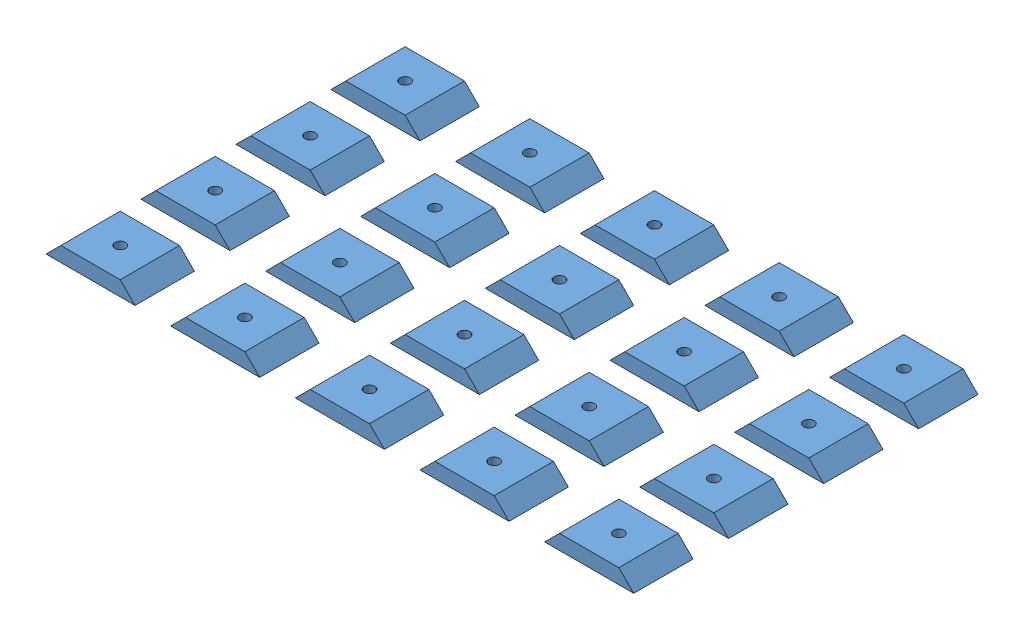
SolidWorks assembly Pressure_Port_Nut_WAterjet_Layout, configuration Default. Lengths in mm.
Overall size (125.73 3.17 73.66).
32 component instances, 2 part files, 3 mates.
Components (placement in the parent):
- Pressure_Port_Cover_Nut-1: Pressure_Port_Cover_Nut [Default] at (-34.8139 9.8282 11.9389) size (19.05 3.17 12.7)
- Pressure_Port_Cover_Nut-3: Pressure_Port_Cover_Nut [Default] at (-8.1439 9.8282 11.9389) size (19.05 3.17 12.7)
- Pressure_Port_Cover_Nut-4: Pressure_Port_Cover_Nut [Default] at (-34.8139 9.8282 32.2589) size (19.05 3.17 12.7)
- Pressure_Port_Cover_Nut-5: Pressure_Port_Cover_Nut [Default] at (-34.8139 9.8282 52.5789) size (19.05 3.17 12.7)
- Pressure_Port_Cover_Nut-6: Pressure_Port_Cover_Nut [Default] at (-34.8139 9.8282 72.8989) size (19.05 3.17 12.7)
- Pressure_Port_Cover_Nut-7: Pressure_Port_Cover_Nut [Default] at (-8.1439 9.8282 32.2589) size (19.05 3.17 12.7)
- Pressure_Port_Cover_Nut-8: Pressure_Port_Cover_Nut [Default] at (-8.1439 9.8282 52.5789) size (19.05 3.17 12.7)
- Pressure_Port_Cover_Nut-9: Pressure_Port_Cover_Nut [Default] at (-8.1439 9.8282 72.8989) size (19.05 3.17 12.7)
- Pressure_Port_Cover_Nut-10: Pressure_Port_Cover_Nut [Default] at (18.5261 9.8282 11.9389) size (19.05 3.17 12.7)
- Pressure_Port_Cover_Nut-11: Pressure_Port_Cover_Nut [Default] at (18.5261 9.8282 32.2589) size (19.05 3.17 12.7)
- Pressure_Port_Cover_Nut-12: Pressure_Port_Cover_Nut [Default] at (18.5261 9.8282 52.5789) size (19.05 3.17 12.7)
- Pressure_Port_Cover_Nut-13: Pressure_Port_Cover_Nut [Default] at (18.5261 9.8282 72.8989) size (19.05 3.17 12.7)
- Pressure_Port_Cover_Nut-14: Pressure_Port_Cover_Nut [Default] at (45.1961 9.8282 11.9389) size (19.05 3.17 12.7)
- Pressure_Port_Cover_Nut-15: Pressure_Port_Cover_Nut [Default] at (45.1961 9.8282 32.2589) size (19.05 3.17 12.7)
- Pressure_Port_Cover_Nut-16: Pressure_Port_Cover_Nut [Default] at (45.1961 9.8282 52.5789) size (19.05 3.17 12.7)
- Pressure_Port_Cover_Nut-17: Pressure_Port_Cover_Nut [Default] at (45.1961 9.8282 72.8989) size (19.05 3.17 12.7)
- Pressure_Port_Cover_Nut-18: Pressure_Port_Cover_Nut [Default] at (71.8661 9.8282 11.9389) size (19.05 3.17 12.7)
- Pressure_Port_Cover_Nut-19: Pressure_Port_Cover_Nut [Default] at (71.8661 9.8282 32.2589) size (19.05 3.17 12.7)
- Pressure_Port_Cover_Nut-20: Pressure_Port_Cover_Nut [Default] at (71.8661 9.8282 52.5789) size (19.05 3.17 12.7)
- Pressure_Port_Cover_Nut-21: Pressure_Port_Cover_Nut [Default] at (71.8661 9.8282 72.8989) size (19.05 3.17 12.7)
- Pressure_Port_Nut_Waterjet_Tabs-1: Pressure_Port_Nut_Waterjet_Tabs [Default] at (-19.5739 12.3682 23.3689) (suppressed, hidden)
- Pressure_Port_Nut_Waterjet_Tabs-2: Pressure_Port_Nut_Waterjet_Tabs [Default] at (-19.5739 12.3682 43.6889) (suppressed, hidden)
- Pressure_Port_Nut_Waterjet_Tabs-3: Pressure_Port_Nut_Waterjet_Tabs [Default] at (-19.5739 12.3682 64.0089) (suppressed, hidden)
- Pressure_Port_Nut_Waterjet_Tabs-4: Pressure_Port_Nut_Waterjet_Tabs [Default] at (7.0961 12.3682 23.3689) (suppressed, hidden)
- Pressure_Port_Nut_Waterjet_Tabs-5: Pressure_Port_Nut_Waterjet_Tabs [Default] at (7.0961 12.3682 43.6889) (suppressed, hidden)
- Pressure_Port_Nut_Waterjet_Tabs-6: Pressure_Port_Nut_Waterjet_Tabs [Default] at (7.0961 12.3682 64.0089) (suppressed, hidden)
- Pressure_Port_Nut_Waterjet_Tabs-7: Pressure_Port_Nut_Waterjet_Tabs [Default] at (33.7661 12.3682 23.3689) (suppressed, hidden)
- Pressure_Port_Nut_Waterjet_Tabs-8: Pressure_Port_Nut_Waterjet_Tabs [Default] at (33.7661 12.3682 43.6889) (suppressed, hidden)
- Pressure_Port_Nut_Waterjet_Tabs-9: Pressure_Port_Nut_Waterjet_Tabs [Default] at (33.7661 12.3682 64.0089) (suppressed, hidden)
- Pressure_Port_Nut_Waterjet_Tabs-10: Pressure_Port_Nut_Waterjet_Tabs [Default] at (60.4361 12.3682 23.3689) (suppressed, hidden)
- Pressure_Port_Nut_Waterjet_Tabs-11: Pressure_Port_Nut_Waterjet_Tabs [Default] at (60.4361 12.3682 43.6889) (suppressed, hidden)
- Pressure_Port_Nut_Waterjet_Tabs-12: Pressure_Port_Nut_Waterjet_Tabs [Default] at (60.4361 12.3682 64.0089) (suppressed, hidden)
Mates (geometry in assembly coordinates):
- Distance1: distance = 2.54 mm aligned: plane of Pressure_Port_Cover_Nut-1 through (-34.8139 9.8282 11.9389) normal (0 -1 0); plane of Pressure_Port_Nut_Waterjet_Tabs-1 through (-19.5739 12.3682 23.3689) normal (0 -1 0)
- Coincident2: coincident: line of Pressure_Port_Cover_Nut-1 through (-15.7639 9.8282 11.9389) axis (0 0 -1); plane of Pressure_Port_Nut_Waterjet_Tabs-1 through (-15.7639 15.5432 19.5589) normal (1 0 0)
- Coincident3: coincident aligned: plane of Pressure_Port_Cover_Nut-1 through (-34.8139 13.0032 11.9389) normal (0 0 1); plane of Pressure_Port_Nut_Waterjet_Tabs-1 through (-15.7639 15.5432 11.9389) normal (0 0 1)
